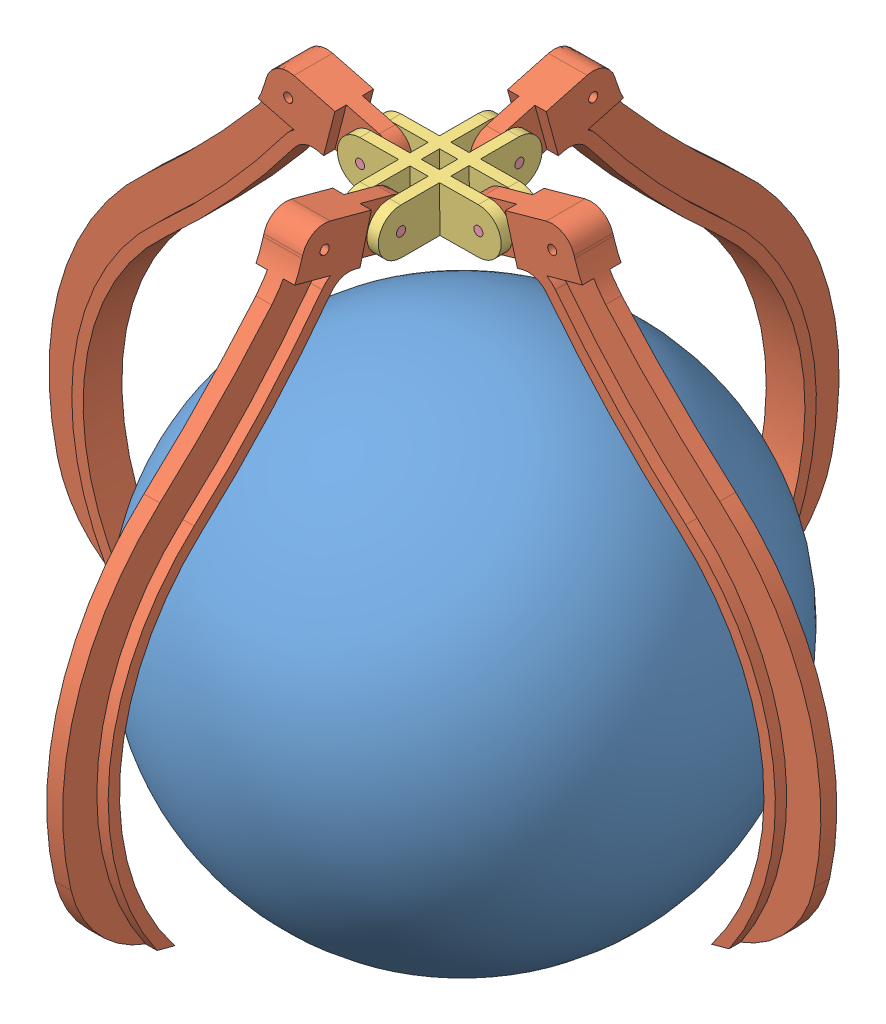
SolidWorks assembly Ensamblaje1, configuration Predeterminado. Lengths in mm.
Overall size (376.97 321.7 376.98).
10 component instances, 4 part files, 12 mates.
Components (placement in the parent):
- Ball_Picker_1-1: Ball_Picker_1 [Predeterminado] at (-103.412 7.3232 220) size (220 220 220)
- Ball_Picker_2-1: Ball_Picker_2 [Predeterminado] at (-102.7862 28.3646 191.9672) x (-0.002355 0.258808 -0.965926) z (0.999959 0.0091 0) size (113.99 249.67 17)
- Ball_Picker_2-2: Ball_Picker_2 [Predeterminado] at (-59.723 28.7564 229.0322) x (0.963531 0.267598 0) z (0 0 1) size (113.99 249.67 17)
- Ball_Picker_2-3: Ball_Picker_2 [Predeterminado] at (-139.8496 28.0273 235.0322) x (-0.968241 0.250019 0) z (0 0 -1) size (113.99 249.67 17)
- Ball_Picker_2-4: Ball_Picker_2 [Predeterminado] at (-96.7864 28.4192 272.0971) x (-0.002355 0.258808 0.965926) z (-0.999959 -0.0091 0) size (113.99 249.67 17)
- Ball_Picker_3-1: Ball_Picker_3 [Predeterminado] at (-75.1691 181.557 223.0322) x (0.999959 0.0091 0) z (0 0 1) size (72.02 20 72.02)
- Ball_Picker_4-1: Ball_Picker_4 [Predeterminado] at (-127.1869 181.0836 223.0322) size (4 4 18)
- Ball_Picker_4-2: Ball_Picker_4 [Predeterminado] at (-110.1776 181.2384 258.0422) x (0 0 -1) z (0.999959 0.0091 0) size (4 4 18)
- Ball_Picker_4-3: Ball_Picker_4 [Predeterminado] at (-75.1691 181.557 223.0322) size (4 4 18)
- Ball_Picker_4-4: Ball_Picker_4 [Predeterminado] at (-92.1783 181.4022 206.0222) x (0 0 1) z (-0.999959 -0.0091 0) size (4 4 18)
Mates (geometry in assembly coordinates):
- Coincidente1: coincident aligned: circle of Ball_Picker_2-2; circle of Ball_Picker_3-1
- Coincidente2: coincident aligned: circle of Ball_Picker_2-1; circle of Ball_Picker_3-1
- Coincidente3: coincident aligned: circle of Ball_Picker_2-4; circle of Ball_Picker_3-1
- Coincidente4: coincident aligned: circle of Ball_Picker_2-3; circle of Ball_Picker_3-1
- Coincidente5: coincident aligned: circle of Ball_Picker_3-1; circle of Ball_Picker_4-1
- Coincidente7: coincident anti-aligned: circle of Ball_Picker_3-1; circle of Ball_Picker_4-4
- Coincidente8: coincident aligned: circle of Ball_Picker_3-1; circle of Ball_Picker_4-3
- Coincidente9: coincident anti-aligned: circle of Ball_Picker_3-1; circle of Ball_Picker_4-2
- Ángulo1: planar angle = 2.879793 rad aligned: line of Ball_Picker_3-1 through (-92.2693 191.4018 258.0422) axis (0 0 -1); line of Ball_Picker_2-4 through (-93.3015 194.934 269.9428) axis (-0.002355 0.258808 0.965926)
- Ángulo2: planar angle = 6.021386 rad aligned: line of Ball_Picker_3-1 through (-75.26 191.5565 241.0322) axis (-0.999959 -0.0091 0); line of Ball_Picker_2-2 through (-45.439 200.1923 241.0322) axis (-0.963531 -0.267598 0)
- Ángulo4: planar angle = 3.403392 rad aligned: line of Ball_Picker_3-1 through (-92.2693 191.4018 223.0322) axis (0 0 -1); line of Ball_Picker_2-1 through (-92.3455 199.7654 176.1237) axis (0.002355 -0.258808 0.965926)
- Ángulo5: planar angle = 6.021386 rad aligned: line of Ball_Picker_2-3 through (-139.2103 194.5163 240.0322) axis (-0.968241 0.250019 0); line of Ball_Picker_3-1 through (-110.2686 191.238 241.0322) axis (-0.999959 -0.0091 0)
